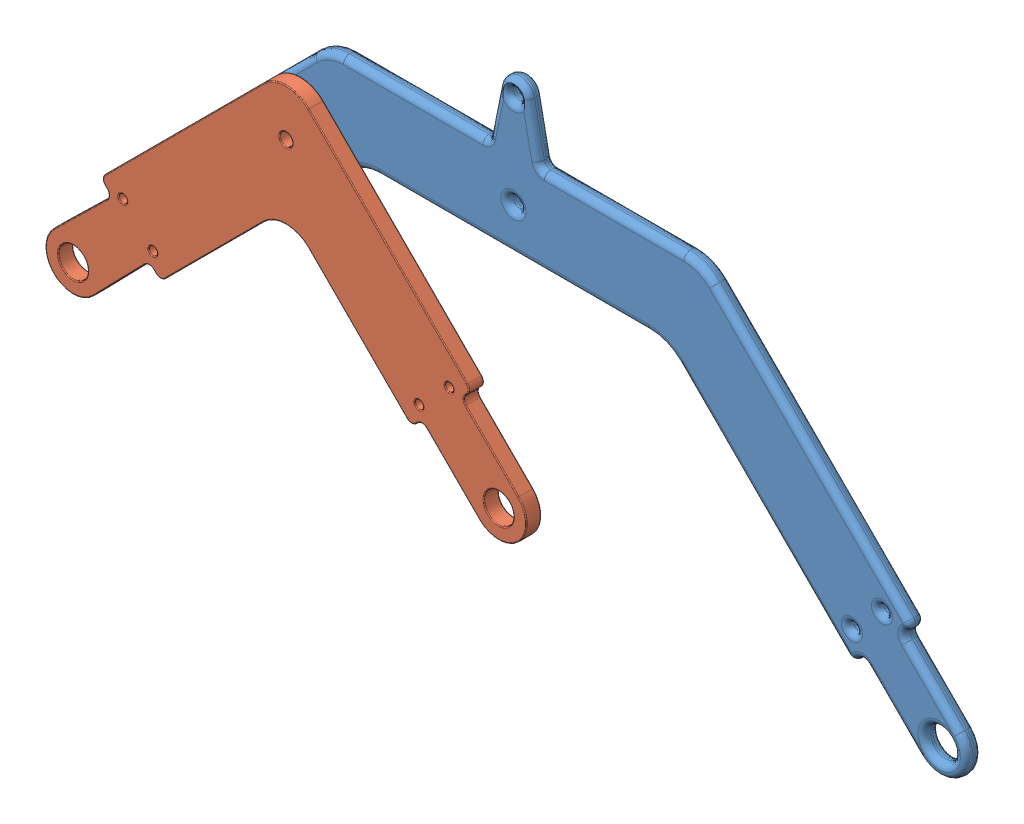
SolidWorks assembly Left Rocker Bogie, configuration Default. Lengths in mm.
Overall size (213 92 7.33).
2 component instances, 2 part files, 2 mates.
Components (placement in the parent):
- rocker-1: rocker [Default] at (-85.8713 13.3725 98.9079) size (170.09 92 4.16)
- Bogie-1: Bogie [Default] at (-85.8713 13.3725 102.4079) size (113 67.54 3.5)
Mates (geometry in assembly coordinates):
- Concentric1: concentric anti-aligned: circle of rocker-1; cylinder of Bogie-1 through (-135.8713 63.3725 102.4079) axis (0 0 1) radius 1.524
- Coincident1: coincident anti-aligned: plane of rocker-1 through (14.1287 13.3725 102.4079) normal (0 0 1); plane of Bogie-1 through (-85.8713 13.3725 102.4079) normal (0 0 -1)
